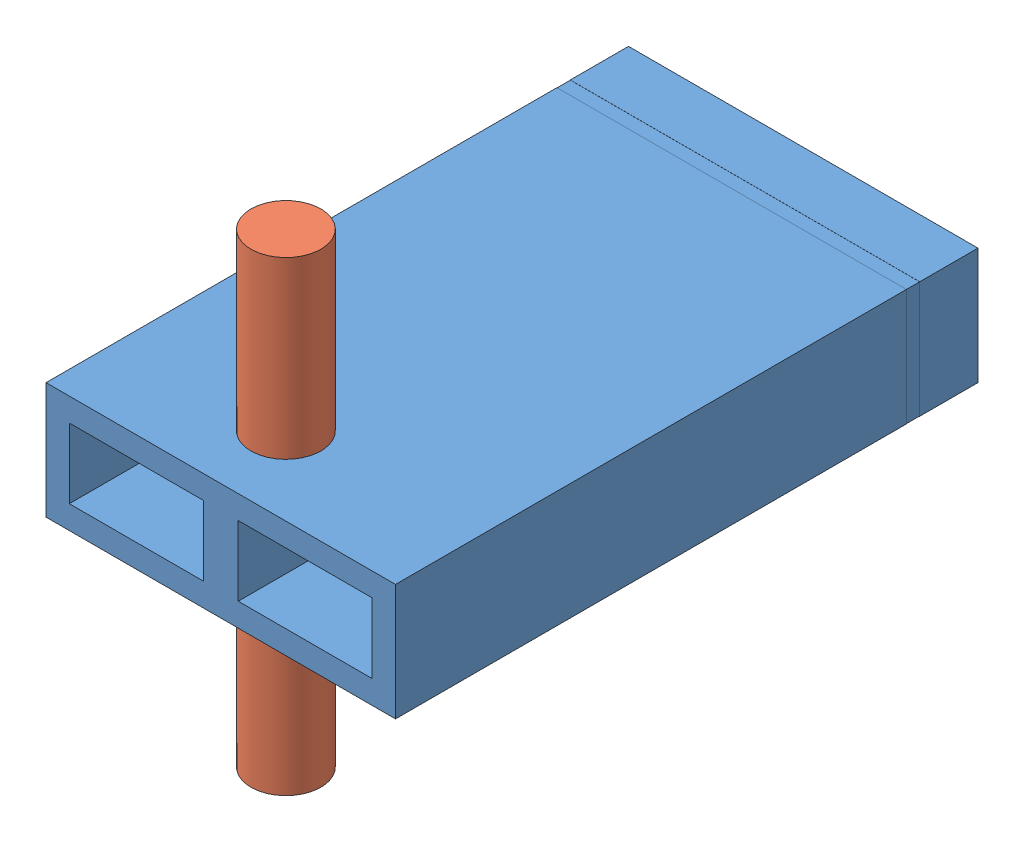
SolidWorks assembly 1114test, configuration Default. Lengths in mm.
Overall size (30 40 50).
3 component instances, 2 part files, 3 mates.
Components (placement in the parent):
- 插头-1: 插头 [默认] at (35.8836 37.3785 13.3418) size (30 12.41 50)
- cylindersensor-1: cylindersensor [Default] at (38.1732 57.3785 54.272) x (1 0 0) z (0 -1 0) size (6 6 15)
- cylindersensor-2: cylindersensor [Default] at (38.1732 17.3785 58.9866) x (1 0 0) z (0 1 0) size (6 6 15)
Mates (geometry in assembly coordinates):
- 重合1: coincident anti-aligned: plane of 插头-1 through (35.8836 32.3785 63.3418) normal (0 -1 0); plane of cylindersensor-2 through (34.7626 50.541 56.6293) normal (0 1 0)
- 重合3: coincident anti-aligned: plane of 插头-1 through (35.8836 42.3785 63.3418) normal (0 1 0); plane of cylindersensor-1 through (34.7626 42.3785 56.6293) normal (0 -1 0)
- 同心1: concentric anti-aligned: cylinder of cylindersensor-1 through (34.7626 42.3785 56.6293) axis (0 1 0) radius 3; cylinder of cylindersensor-2 through (34.7626 32.3785 56.6293) axis (0 -1 0) radius 3
